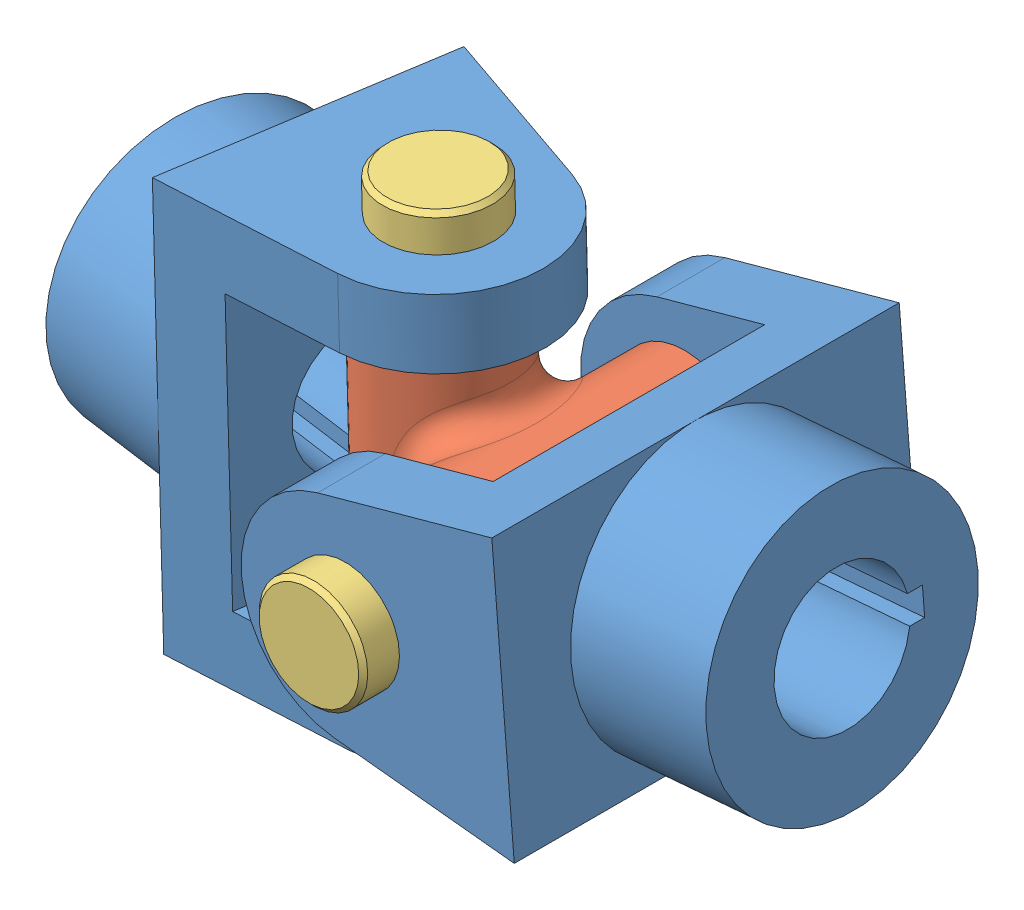
SolidWorks assembly Assem1, configuration Default. Lengths in mm.
Overall size (160.44 113.81 113).
9 component instances, 5 part files, 19 mates.
Components (placement in the parent):
- 1-1: 1 [Default] at (23.4054 27.5144 100.5514) x (0.996585 0.08257 0) z (0 0 1) size (88 60 90)
- 2-1: 2 [Default] at (-22.1545 25.0483 100.5514) x (0.999611 0.027886 0) z (0 0 1) size (53 60 60)
- 3-1: 3 [Default] at (-24.2459 100.0191 100.5514) x (-0.027886 0.999611 0) z (-0.327842 -0.009146 0.944688) size (113 24 24)
- 4-1: 4 [Default] at (-21.5131 2.0572 100.5514) x (-0.944321 -0.026344 -0.32797) z (0.327842 0.009146 -0.944688) size (24 8 24)
- 5-1: 5 [Default] at (-21.6246 6.0556 100.5514) x (0.327842 0.009146 -0.944688) z (0.944064 0.034433 0.327959) size (30 4 4)
- 1-3: 1 [Default] at (-38.9048 54.5926 67.5733) x (-0.986687 -0.027526 -0.160284) z (-0.027886 0.999611 0) size (88 60 90)
- 3-2: 3 [Default] at (0 55.678 145.5514) x (0 0 1) z (-0.86105 -0.508521 0) size (113 24 24)
- 4-2: 4 [Default] at (0 55.678 47.5514) x (0.508521 -0.86105 0) z (-0.86105 -0.508521 0) size (24 8 24)
- 5-2: 5 [Default] at (0 55.678 51.5514) x (0.86105 0.508521 0) z (0 0 1) size (30 4 4)
Mates (geometry in assembly coordinates):
- Concentric1: concentric anti-aligned: cylinder of 1-1 through (0 55.678 20.5514) axis (0 0 1) radius 8; cylinder of 2-1 through (0 55.678 130.5514) axis (0 0 -1) radius 8
- Coincident2: coincident anti-aligned: plane of 1-1 through (22.4088 27.4318 70.5514) normal (0 0 1); plane of 2-1 through (0 55.678 70.5514) normal (0 0 -1)
- Concentric3: concentric anti-aligned: cylinder of 2-1 through (-23.8276 85.0249 100.5514) axis (0.027886 -0.999611 0) radius 8; cylinder of 1-3 through (-20.7602 -24.9323 100.5514) axis (-0.027886 0.999611 0) radius 8
- Coincident3: coincident anti-aligned: plane of 2-1 through (-23.8276 85.0249 100.5514) normal (-0.027886 0.999611 0); plane of 1-3 through (-38.7547 84.6085 67.7336) normal (0.027886 -0.999611 0)
- Concentric7: concentric aligned: cylinder of 3-1 through (-21.3179 -4.9401 100.5514) axis (-0.027886 0.999611 0) radius 8; cylinder of 1-3 through (-20.7602 -24.9323 100.5514) axis (-0.027886 0.999611 0) radius 8
- Coincident4: coincident anti-aligned: plane of 3-1 through (-24.2459 100.0191 100.5514) normal (0.027886 -0.999611 0); plane of 1-3 through (-6.3588 100.5181 133.85) normal (-0.027886 0.999611 0)
- Lock1: lock: unknown of 2-1; unknown of 1-3
- Concentric8: concentric anti-aligned: cylinder of 1-1 through (0 55.678 20.5514) axis (0 0 1) radius 8
- Coincident6: coincident: plane of 1-1 through (-25.3986 83.6764 145.5514) normal (0 0 1)
- Concentric10: concentric anti-aligned: cylinder of 3-1 through (-21.3179 -4.9401 100.5514) axis (-0.027886 0.999611 0) radius 8; cylinder of 4-1 through (-21.7362 10.0541 100.5514) axis (0.027886 -0.999611 0) radius 8
- Concentric11: concentric anti-aligned: cylinder of 3-1 through (-26.2144 5.9276 113.777) axis (0.327842 0.009146 -0.944688) radius 2; cylinder of 4-1 through (-15.7235 6.2203 83.547) axis (-0.327842 -0.009146 0.944688) radius 2
- Concentric12: concentric aligned: cylinder of 4-1 through (-15.7235 6.2203 83.547) axis (-0.327842 -0.009146 0.944688) radius 2; cylinder of 5-1 through (-16.707 6.1928 86.3811) axis (-0.327842 -0.009146 0.944688) radius 2
- Width1: width: plane of 5-1 through (-26.5423 5.9185 114.7217) normal (-0.327842 -0.009146 0.944688); plane of 4-1 through (-16.707 6.1928 86.3811) normal (0.327842 0.009146 -0.944688); cylinder of 5-1 through (-21.7362 10.0541 100.5514) axis (0.027886 -0.999611 0) radius 12
- Concentric13: concentric aligned: cylinder of 1-1 through (0 55.678 20.5514) axis (0 0 1) radius 8; cylinder of 3-2 through (0 55.678 40.5514) axis (0 0 1) radius 8
- Coincident9: coincident anti-aligned: plane of 1-1 through (-25.3986 83.6764 145.5514) normal (0 0 1); plane of 3-2 through (0 55.678 145.5514) normal (0 0 -1)
- Concentric14: concentric anti-aligned: cylinder of 3-2 through (0 55.678 40.5514) axis (0 0 1) radius 8; cylinder of 4-2 through (0 55.678 55.5514) axis (0 0 -1) radius 8
- Concentric15: concentric aligned: cylinder of 3-2 through (-12.0547 48.5587 51.5514) axis (0.86105 0.508521 0) radius 2; cylinder of 4-2 through (-15.4989 46.5246 51.5514) axis (0.86105 0.508521 0) radius 2
- Concentric16: concentric anti-aligned: cylinder of 4-2 through (-15.4989 46.5246 51.5514) axis (0.86105 0.508521 0) radius 2; cylinder of 5-2 through (12.9157 63.3058 51.5514) axis (-0.86105 -0.508521 0) radius 2
- Width2: width: plane of 5-2 through (12.9157 63.3058 51.5514) normal (0.86105 0.508521 0); plane of 4-2 through (-12.9157 48.0502 51.5514) normal (-0.86105 -0.508521 0); cylinder of 5-2 through (0 55.678 55.5514) axis (0 0 -1) radius 12
